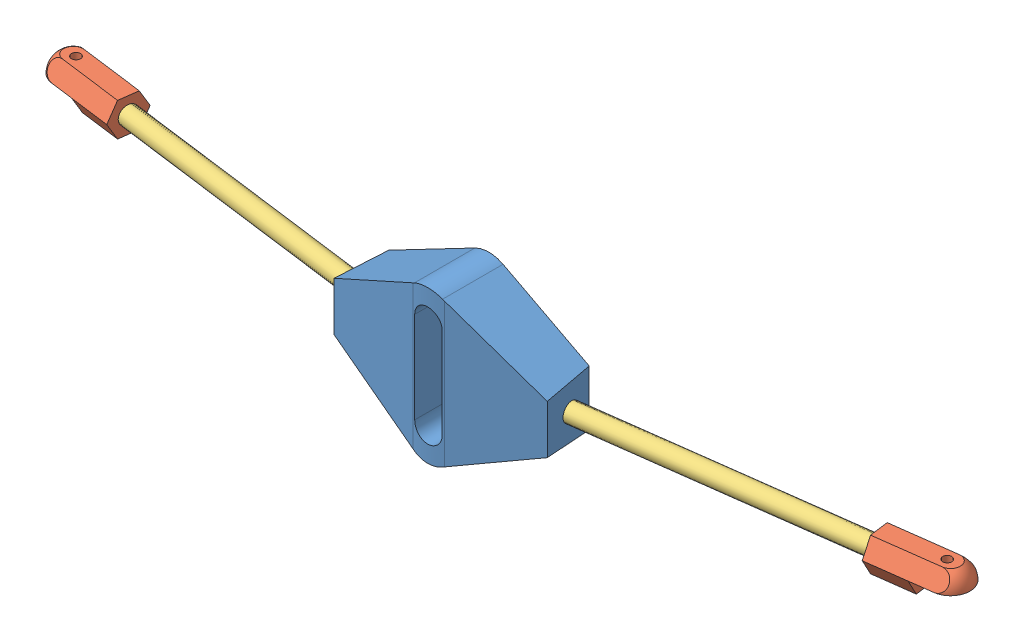
SolidWorks assembly Lenkstange, configuration Standard. Lengths in mm.
Overall size (151.12 25 17.41).
5 component instances, 3 part files, 12 mates.
Components (placement in the parent):
- Lenkstange-Mittelstück-1: Lenkstange-Mittelstück [Standard] at origin size (35 25 10.06)
- Gelenkbolzen-1: Gelenkbolzen [M3] at (-61.5856 0 -2.4112) x (0 1 0) z (0.991445 0 0.130526) size (5.5 6.35 13.68)
- Gewindestange-1: Gewindestange [M3x60] at (-37.7909 0 0.7214) x (-0.130526 0 0.991445) z (-0.991445 0 -0.130526) size (3 3 60)
- Gewindestange-3: Gewindestange [M3x60] at (37.7909 0 0.7214) x (-0.130526 0 -0.991445) z (-0.991445 0 0.130526) size (3 3 60)
- Gelenkbolzen-5: Gelenkbolzen [M3] at (61.5856 0 -2.4113) x (0 1 0) z (-0.991445 0 0.130526) size (5.5 6.35 13.68)
Mates (geometry in assembly coordinates):
- Konzentrisch1: concentric aligned: cylinder of Gelenkbolzen-1 through (-67.5342 0 -3.1944) axis (0.991445 0 0.130526) radius 1.23; cylinder of Gewindestange-1 through (-67.5342 0 -3.1944) axis (0.991445 0 0.130526) radius 1.5
- Deckungsgleich2: coincident anti-aligned: plane of Gelenkbolzen-1 through (-67.5342 0 -3.1944) normal (0.991445 0 0.130526); plane of Gewindestange-1 through (-67.5342 0 -3.1944) normal (-0.991445 0 -0.130526)
- Deckungsgleich4: coincident aligned: plane of Lenkstange-Mittelstück-1 through (0 0 0) normal (0 1 0); plane of assembly through (0 0 0) normal (0 1 0)
- Deckungsgleich5: coincident aligned: plane of Lenkstange-Mittelstück-1 through (0 0 0) normal (0 0 1); plane of assembly through (0 0 0) normal (0 0 1)
- Konzentrisch2: concentric anti-aligned: cylinder of Lenkstange-Mittelstück-1 through (-5.0153 0 5.0364) axis (-0.991445 0 -0.130526) radius 1.23; cylinder of Gewindestange-1 through (-67.5342 0 -3.1944) axis (0.991445 0 0.130526) radius 1.5
- Deckungsgleich6: coincident aligned: plane of Gelenkbolzen-1; plane of assembly through (0 0 0) normal (0 1 0)
- Abstand1: distance = 71.5 mm: line of Gelenkbolzen-1 through (-71.5 0 -3.7165) axis (0 1 0); plane of assembly
- Deckungsgleich8: coincident aligned: plane of Gewindestange-1; plane of assembly through (0 0 0) normal (0 1 0)
- Konzentrisch3: concentric anti-aligned: cylinder of Gewindestange-3 through (8.0475 0 4.6372) axis (0.991445 0 -0.130526) radius 1.5; cylinder of Gelenkbolzen-5 through (67.5342 0 -3.1944) axis (-0.991445 0 0.130526) radius 1.23
- Deckungsgleich9: coincident anti-aligned: plane of Gewindestange-3 through (67.5342 0 -3.1944) normal (0.991445 0 -0.130526); plane of Gelenkbolzen-5 through (67.5342 0 -3.1944) normal (-0.991445 0 0.130526)
- Symmetrisch1: symmetric aligned: plane of Lenkstange-Mittelstück-1 through (0 0 0) normal (1 0 0); plane of Gewindestange-1 through (-8.0475 0 4.6372) normal (0.991445 0 0.130526); plane of Gewindestange-3 through (8.0475 0 4.6372) normal (-0.991445 0 0.130526)
- Deckungsgleich10: coincident anti-aligned: plane of Gewindestange-3; plane of assembly through (0 0 0) normal (0 1 0)
